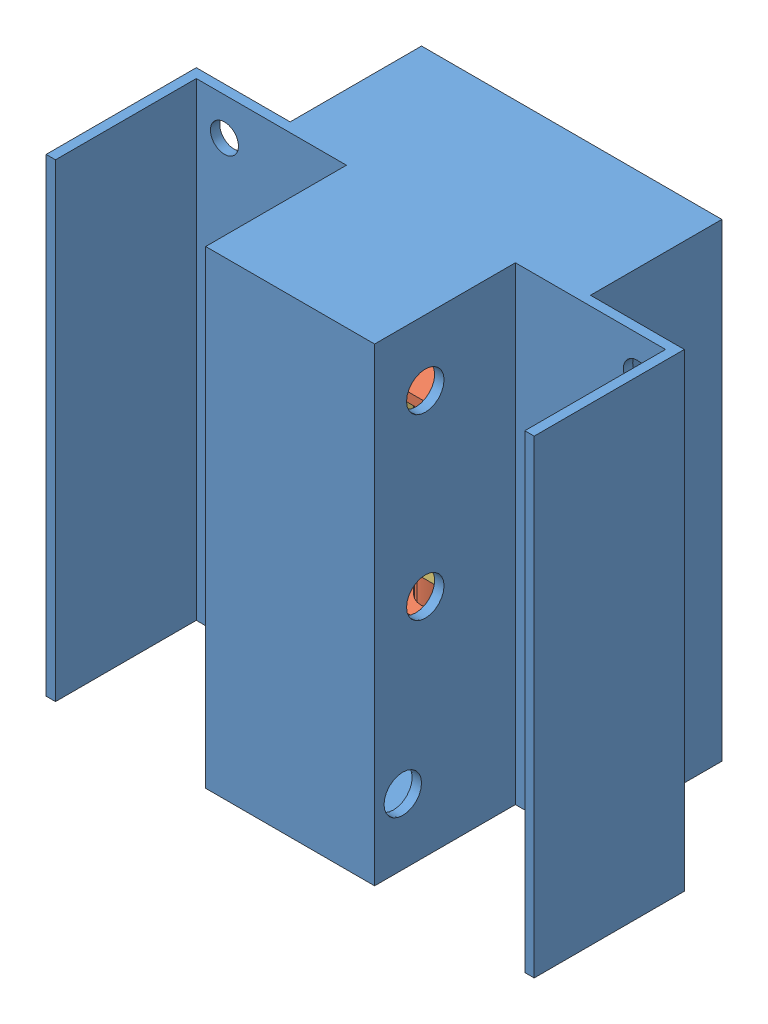
SolidWorks assembly Assemblage verin, configuration Défaut. Lengths in mm.
Overall size (260 250 150).
6 component instances, 5 part files, 12 mates.
Components (placement in the parent):
- chassis inferieur(verin)-1: chassis inferieur(verin) [Défaut] at (20.6148 -109.6944 330) size (260 250 150)
- verin-1: verin [Défaut] at (5.6148 -68.1653 225.1312) x (1 0 0) z (0 1 0) size (40 40 135)
- verin-2: verin [Défaut] at (-54.3852 -67.6807 225.1312) x (0 0 1) z (0 1 0) size (40 40 135)
- support verin 2-1: support verin 2 [Défaut] at (-16.3044 -34.6944 220.4827) x (-1 0 0) z (0 1 0) size (150 70 60)
- detacheur-1: detacheur [Défaut] at (-69.3374 -104.6944 211.8236) x (-1 0 0) z (0 1 0) size (90 30 25)
- moteur-2: moteur [Défaut] at (-24.3374 -43.1899 226.8236) x (0.643907 0 -0.765104) z (0 -1 0) size (20 20 40)
Mates (geometry in assembly coordinates):
- Coaxiale1: concentric anti-aligned: cylinder of chassis inferieur(verin)-1 through (5.6148 -99.6944 225.1312) axis (0 -1 0) radius 20; cylinder of verin-1 through (5.6148 -98.1653 225.1312) axis (0 1 0) radius 17.5
- Coaxiale2: concentric anti-aligned: cylinder of chassis inferieur(verin)-1 through (-54.3852 -99.6944 225.1312) axis (0 -1 0) radius 20; cylinder of verin-2 through (-54.3852 -97.6807 225.1312) axis (0 1 0) radius 17.5
- Coïncidente4: coincident anti-aligned: plane of chassis inferieur(verin)-1 through (50.6148 135.3056 185) normal (-1 0 0); plane of support verin 2-1 through (50.6148 -29.6944 255) normal (1 0 0)
- Coïncidente5: coincident anti-aligned: plane of chassis inferieur(verin)-1 through (20.6148 -109.6944 255) normal (0 0 -1); plane of support verin 2-1 through (50.6148 -29.6944 255) normal (0 0 1)
- Parallèle1: parallel aligned: plane of verin-1 through (-14.3852 36.8347 205.1312) normal (0 0 -1); plane of support verin 2-1 through (50.6148 -29.6944 185) normal (0 0 -1)
- Parallèle2: parallel aligned: plane of verin-2 through (-34.3852 37.3193 205.1312) normal (0 0 -1); plane of support verin 2-1 through (50.6148 -29.6944 185) normal (0 0 -1)
- Distance3: distance = 70 mm anti-aligned: plane of support verin 2-1 through (-16.3044 -34.6944 220.4827) normal (0 -1 0); plane of chassis inferieur(verin)-1 through (15.6148 -104.6944 260) normal (0 1 0)
- Coïncidente17: coincident anti-aligned: plane of chassis inferieur(verin)-1 through (15.6148 -104.6944 260) normal (0 1 0); plane of detacheur-1 through (-69.3374 -104.6944 211.8236) normal (0 -1 0)
- Coaxiale6: concentric aligned: cylinder of detacheur-1 through (-24.3374 -79.6944 226.8236) axis (0 -1 0) radius 5; cylinder of moteur-2 through (-24.3374 -78.1899 226.8236) axis (0 -1 0) radius 5
- Distance5: distance = 8.4955 mm anti-aligned: plane of support verin 2-1 through (-16.3044 -34.6944 220.4827) normal (0 -1 0); plane of moteur-2 through (-24.3374 -43.1899 226.8236) normal (0 1 0)
- Parallèle5: parallel aligned: plane of chassis inferieur(verin)-1 through (20.6148 -109.6944 185) normal (0 0 -1); plane of detacheur-1 through (-69.3374 -99.6944 211.8236) normal (0 0 -1)
- Distance9: distance = 10 mm: cylinder of moteur-2 through (-24.3374 -83.1899 226.8236) axis (0 1 0) radius 10; cylinder of verin-1 through (5.6148 31.8347 225.1312) axis (0 -1 0) radius 10
